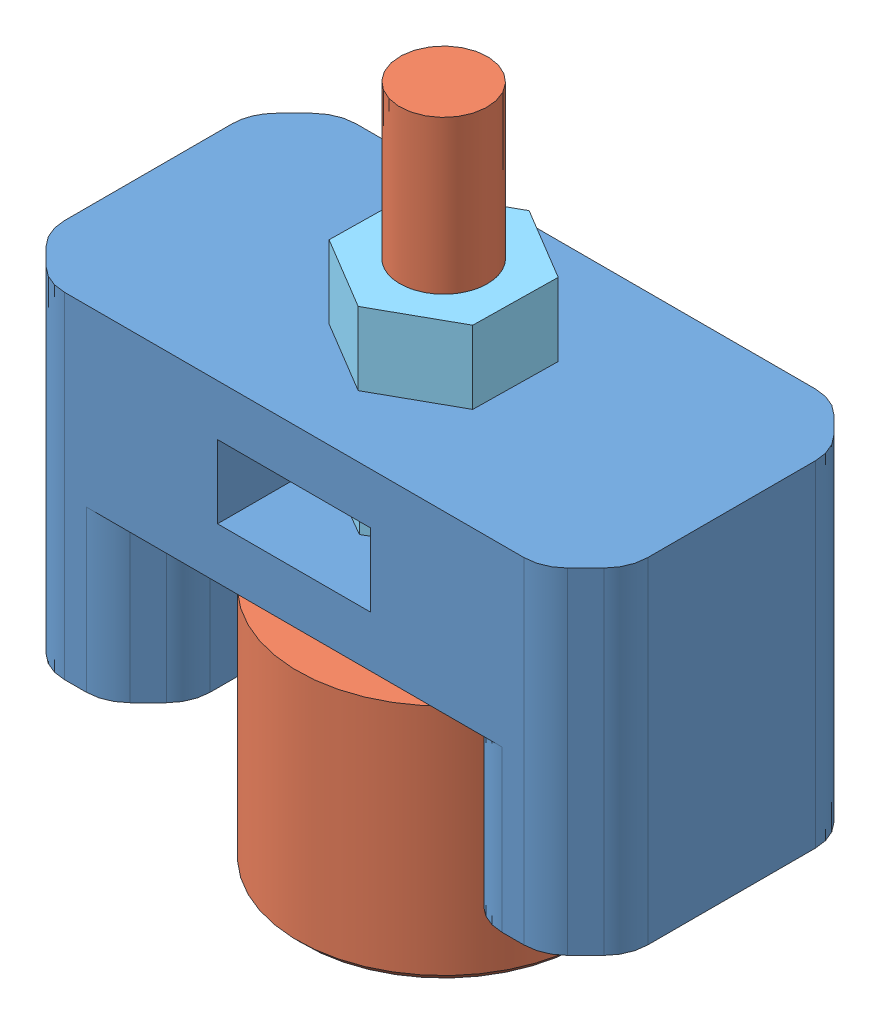
SolidWorks assembly Assemblage Roue Porteuse V2, configuration Défaut. Lengths in mm.
Overall size (40 48.37 20.68).
7 component instances, 5 part files, 13 mates.
Components (placement in the parent):
- Support Bille porteuse V2-1: Support Bille porteuse V2 [Défaut] at (-2.1983 -9.4956 40) size (40 23 20)
- Bille porteuse ALWAYE D12_7-1: Bille porteuse ALWAYE D12_7 [Défaut] at (-1.9483 -6.9983 40) x (-0.034703 0 0.999398) z (-0.999398 0 -0.034703) size (20 46.5 20)
- Bille D12-1: Bille D12 [Défaut] at (-1.9483 -13.3717 40) x (-0.8229 0 0.568186) z (-0.568186 0 -0.8229) size (12 12 12)
- Insert M4-1: Insert M4 [Défaut] at (-17.1983 -9.4956 40) x (1 0 0) z (0 1 0) size (7 7 8)
- Insert M4-2: Insert M4 [Défaut] at (12.8017 -9.4956 40) x (1 0 0) z (0 1 0) size (7 7 8)
- Ecrou M6-3: Ecrou M6 [Défaut] at (-1.9483 13.5044 40) x (0.999888 0 0.014972) z (-0.014972 0 0.999888) size (10 5 11.55)
- Ecrou M6-4: Ecrou M6 [Défaut] at (-1.9483 5.0044 40) size (10 5 11.55)
Mates (geometry in assembly coordinates):
- Coïncidente3: coincident anti-aligned: plane of Support Bille porteuse V2-1 through (-2.1983 -8.4956 40) normal (0 -1 0); plane of Insert M4-2 through (12.8017 -8.4956 40) normal (0 1 0)
- Coïncidente4: coincident anti-aligned: plane of Support Bille porteuse V2-1 through (-2.1983 -8.4956 40) normal (0 -1 0); plane of Insert M4-1 through (-17.1983 -8.4956 40) normal (0 1 0)
- Coaxiale4: concentric anti-aligned: circle of Support Bille porteuse V2-1; circle of Insert M4-1
- Coaxiale5: concentric anti-aligned: circle of Support Bille porteuse V2-1; circle of Insert M4-2
- Coaxiale6: concentric: cylinder of Bille porteuse ALWAYE D12_7-1 through (-1.9483 -16.9983 40) axis (0 1 0) radius 6.75; sphere of Bille D12-1
- Tangent5: tangent: circle of Bille porteuse ALWAYE D12_7-1; sphere of Bille D12-1
- Verrouiller1: lock: unknown of Bille porteuse ALWAYE D12_7-1; unknown of Bille D12-1
- Coïncidente5: coincident anti-aligned: plane of Support Bille porteuse V2-1 through (3.0517 10.0044 30) normal (-1 0 0); plane of Ecrou M6-4 through (3.0517 10.0044 37.1132) normal (1 0 0)
- Coaxiale7: concentric aligned: cylinder of Bille porteuse ALWAYE D12_7-1 through (-1.9483 29.0017 40) axis (0 -1 0) radius 3; cylinder of Ecrou M6-4 through (-1.9483 10.0044 40) axis (0 -1 0) radius 3
- Coïncidente6: coincident anti-aligned: plane of Support Bille porteuse V2-1 through (-2.1983 5.0044 40) normal (0 1 0); plane of Ecrou M6-4 through (-1.9483 5.0044 40) normal (0 -1 0)
- Coaxiale8: concentric aligned: cylinder of Bille porteuse ALWAYE D12_7-1 through (-1.9483 29.0017 40) axis (0 -1 0) radius 3; cylinder of Ecrou M6-3 through (-1.9483 18.5044 40) axis (0 -1 0) radius 3
- Coïncidente7: coincident anti-aligned: plane of Support Bille porteuse V2-1 through (-2.1983 13.5044 40) normal (0 1 0); plane of Ecrou M6-3 through (-1.9483 13.5044 40) normal (0 -1 0)
- Coïncidente8: coincident: point of Support Bille porteuse V2-1; unknown of Ecrou M6-4
